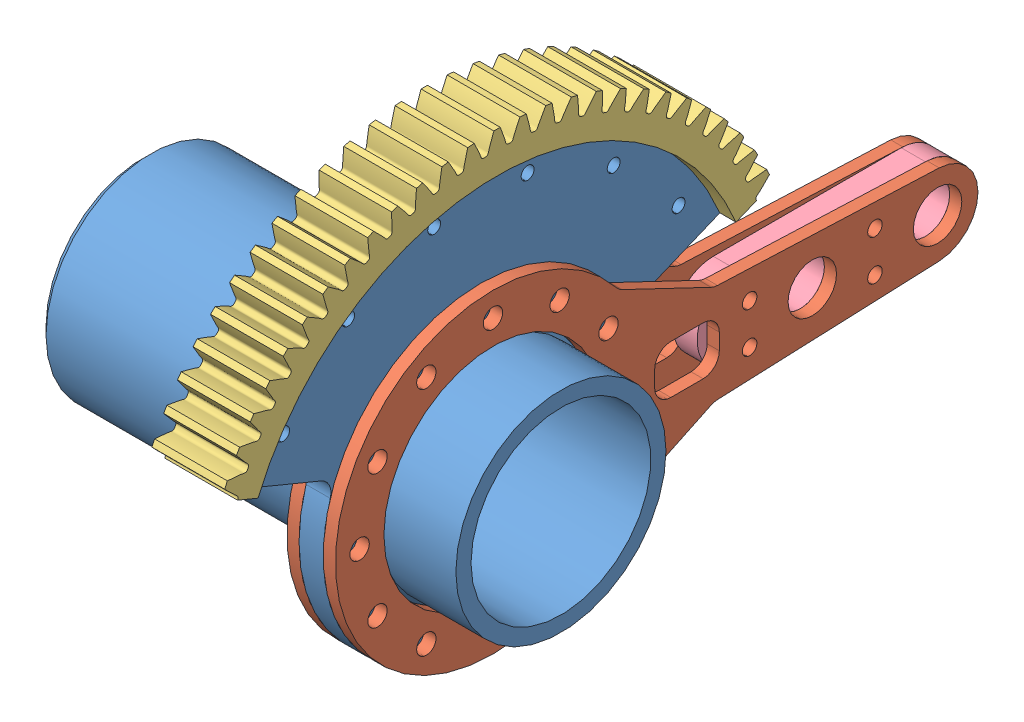
SolidWorks assembly hip-front-new-2012-09-04, configuration Default. Lengths in mm.
Overall size (51.7 69.32 160.65).
5 component instances, 4 part files, 12 mates.
Components (placement in the parent):
- abs-hip-front-2012-09-04-1: abs-hip-front-2012-09-04 [Default] at (-57.0839 1.2367 -1.8747) size (51.7 52.5 128.76)
- carbon-plat-hip-front-1: carbon-plat-hip-front [Default] at (-60.0839 1.2367 -1.8747) x (0 0 -1) z (1 0 0) size (79 38 1.5)
- carbon-plat-hip-front-2: carbon-plat-hip-front [Default] at (-55.5839 1.2367 -1.8747) x (0 0 -1) z (1 0 0) size (79 38 1.5)
- Part3-1: Part3 [Default] at (-58.0839 1.2367 -1.8747) x (1 0 0) z (0 -0.382683 -0.92388) size (9 36.98 62.27)
- hip-front-fudder-1: hip-front-fudder [Default] at (-57.0839 1.2367 -56.8747) x (0 0 1) z (1 0 0) size (33.25 10 3)
Mates (geometry in assembly coordinates):
- Coincident1: coincident anti-aligned: plane of abs-hip-front-2012-09-04-1 through (-58.5839 6.2116 10.1357) normal (-1 0 0); plane of carbon-plat-hip-front-1 through (-58.5839 1.2367 -56.8747) normal (1 0 0)
- Concentric1: concentric aligned: cylinder of abs-hip-front-2012-09-04-1 through (-57.0839 1.2367 -1.8747) axis (-1 0 0) radius 13; cylinder of carbon-plat-hip-front-1 through (-58.5839 1.2367 -1.8747) axis (-1 0 0) radius 14
- Concentric2: concentric aligned: cylinder of abs-hip-front-2012-09-04-1 through (-57.0839 1.2367 -1.8747) axis (-1 0 0) radius 13; cylinder of carbon-plat-hip-front-2 through (-54.0839 1.2367 -1.8747) axis (-1 0 0) radius 14
- Coincident2: coincident anti-aligned: plane of abs-hip-front-2012-09-04-1 through (-55.5839 6.2116 10.1357) normal (1 0 0); plane of carbon-plat-hip-front-2 through (-55.5839 1.2367 -56.8747) normal (-1 0 0)
- Concentric3: concentric aligned: cylinder of carbon-plat-hip-front-1 through (-58.5839 1.2367 -56.8747) axis (-1 0 0) radius 3; cylinder of carbon-plat-hip-front-2 through (-54.0839 1.2367 -56.8747) axis (-1 0 0) radius 3
- Concentric4: concentric anti-aligned: cylinder of abs-hip-front-2012-09-04-1 through (-57.0839 1.2367 -1.8747) axis (-1 0 0) radius 31.5; cylinder of Part3-1 through (-58.0839 1.2367 -1.8747) axis (1 0 0) radius 32
- Parallel1: parallel aligned: plane of carbon-plat-hip-front-1; plane of assembly through (0 0 0) normal (0 1 0)
- Concentric5: concentric anti-aligned: cylinder of carbon-plat-hip-front-1 through (-58.5839 1.2367 -56.8747) axis (-1 0 0) radius 3; cylinder of hip-front-fudder-1 through (-55.5839 1.2367 -56.8747) axis (1 0 0) radius 3
- Coincident6: coincident anti-aligned: plane of carbon-plat-hip-front-1 through (-58.5839 1.2367 -56.8747) normal (1 0 0); plane of hip-front-fudder-1 through (-58.5839 1.2367 -33.6247) normal (-1 0 0)
- Concentric6: concentric anti-aligned: cylinder of carbon-plat-hip-front-2 through (-54.0839 1.2367 -41.3747) axis (-1 0 0) radius 3; cylinder of hip-front-fudder-1 through (-55.5839 1.2367 -41.3747) axis (1 0 0) radius 3
- Coincident7: coincident anti-aligned: plane of abs-hip-front-2012-09-04-1 through (-59.5839 13.2913 27.2275) normal (-1 0 0); plane of Part3-1 through (-59.5839 25.2576 -11.8245) normal (1 0 0)
- Coincident8: coincident aligned: plane of abs-hip-front-2012-09-04-1 through (-58.5839 13.2913 -30.977) normal (0 -0.92388 -0.382683); plane of Part3-1 through (-62.5839 1.2367 -1.8747) normal (0 -0.92388 -0.382683)
